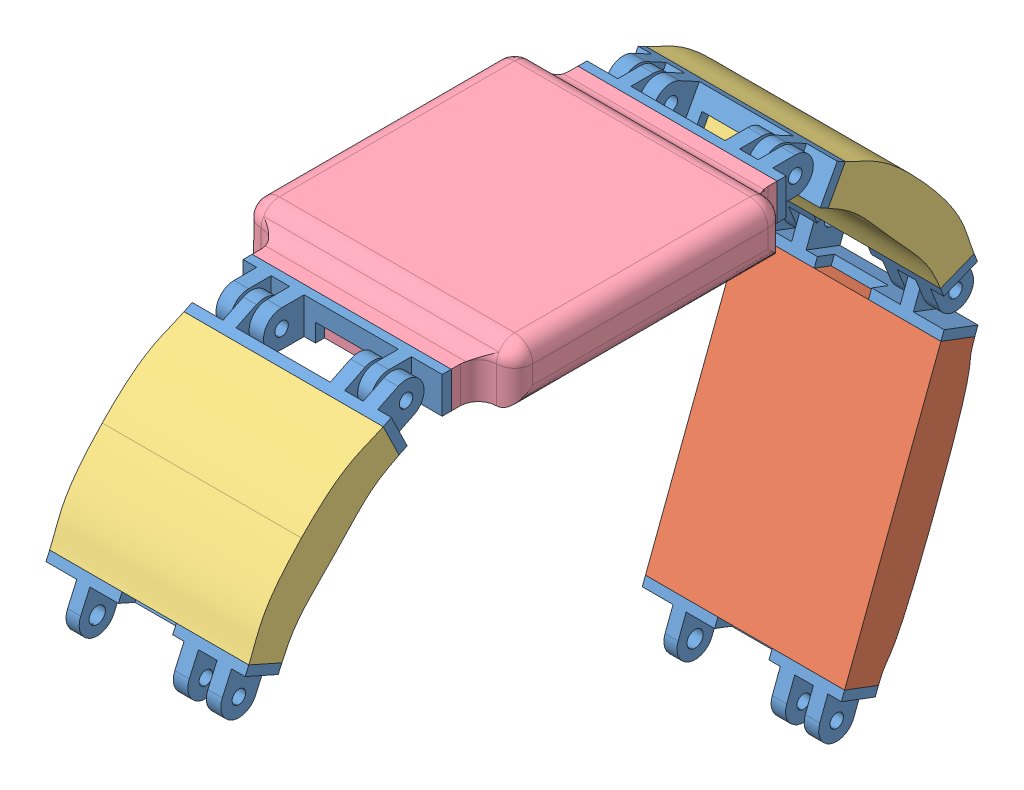
SolidWorks assembly Assem1, configuration Default. Lengths in mm.
Overall size (30 60.99 84.41).
12 component instances, 4 part files, 27 mates.
Components (placement in the parent):
- moddem-1: moddem [Default] at (41.8635 -9.7694 -15.7853) x (1 0 0) z (0 0.934966 -0.354736) size (22 4 5.5)
- moddem-2: moddem [Default] at (41.8635 -44.3632 -2.66) x (-1 0 0) z (0 -0.934966 0.354736) size (22 4 5.5)
- moddem-3: moddem [Default] at (41.8635 10.048 44.925) size (22 4 5.5)
- moddem-4: moddem [Default] at (41.8635 10.048 1.925) x (-1 0 0) z (0 0 -1) size (22 4 5.5)
- moddem-5: moddem [Default] at (41.8635 10.048 44.925) x (-1 0 0) z (0 0.438284 -0.898836) size (22 4 5.5)
- moddem-6: moddem [Default] at (41.8635 -9.0688 63.3894) x (-1 0 0) z (0 -0.913506 0.406825) size (22 4 5.5)
- moddem-7: moddem [Default] at (41.8635 -9.7694 -15.7853) x (-1 0 0) z (0 -0.928574 -0.371147) size (22 4 5.5)
- moddem-8: moddem [Default] at (41.8635 10.048 1.925) x (1 0 0) z (0 0.472761 0.881191) size (22 4 5.5)
- module1-1: module1 [Default] at (30.8635 -26.4386 -7.5684) x (1 0 0) z (0 0.934966 -0.354736) size (22 5 30)
- module4-2: module4 [Default] at (30.8635 0.3363 -7.1506) x (1 0 0) z (0 0.745635 0.666355) size (22 6 21.37)
- module4-1: module4 [Default] at (30.8635 0.695 54.3698) x (1 0 0) z (0 -0.719273 0.694728) size (22 6 21.37)
- module3-1: module3 [Default] at (41.8635 8.048 23.425) x (0 0 1) z (-1 0 0) size (36 6 30)
Mates (geometry in assembly coordinates):
- Coincident1: coincident anti-aligned: plane of module1-1 through (52.8635 -12.3323 -12.6738) normal (0 0.934966 -0.354736); plane of moddem-1 through (30.8635 -13.0418 -14.5437) normal (0 -0.934966 0.354736)
- Coincident2: coincident aligned: line of module1-1 through (52.8635 -13.7513 -16.4136) axis (0 0.354736 0.934966); line of moddem-1 through (52.8635 -13.7513 -16.4136) axis (0 0.354736 0.934966)
- Coincident3: coincident anti-aligned: line of module1-1 through (52.8635 -13.7513 -16.4136) axis (-1 0 0); line of moddem-1 through (30.8635 -13.7513 -16.4136) axis (1 0 0)
- Coincident4: coincident anti-aligned: plane of module1-1 through (52.8635 -40.3813 -2.0317) normal (0 -0.934966 0.354736); plane of moddem-2 through (52.8635 -41.0908 -3.9016) normal (0 0.934966 -0.354736)
- Coincident5: coincident anti-aligned: line of module1-1 through (52.8635 -40.3813 -2.0317) axis (0 -0.354736 -0.934966); line of moddem-2 through (52.8635 -41.8002 -5.7715) axis (0 0.354736 0.934966)
- Coincident6: coincident aligned: line of module1-1 through (52.8635 -41.8002 -5.7715) axis (-1 0 0); line of moddem-2 through (52.8635 -41.8002 -5.7715) axis (-1 0 0)
- Coincident7: coincident anti-aligned: plane of module3-1 through (41.8635 12.048 41.425) normal (0 0 1); plane of moddem-3 through (30.8635 10.048 41.425) normal (0 0 -1)
- Coincident8: coincident anti-aligned: line of module3-1 through (52.8635 12.048 41.425) axis (-1 0 0); line of moddem-3 through (30.8635 12.048 41.425) axis (1 0 0)
- Coincident9: coincident aligned: line of module3-1 through (52.8635 12.048 41.425) axis (0 -1 0); line of moddem-3 through (52.8635 12.048 41.425) axis (0 -1 0)
- Coincident10: coincident anti-aligned: plane of module3-1 through (41.8635 12.048 5.425) normal (0 0 -1); plane of moddem-4 through (52.8635 10.048 5.425) normal (0 0 1)
- Coincident11: coincident aligned: line of module3-1 through (52.8635 12.048 5.425) axis (-1 0 0); line of moddem-4 through (52.8635 12.048 5.425) axis (-1 0 0)
- Coincident12: coincident aligned: line of module3-1 through (52.8635 12.048 5.425) axis (0 -1 0); line of moddem-4 through (52.8635 12.048 5.425) axis (0 -1 0)
- Coincident13: coincident anti-aligned: plane of module4-1 through (52.8635 -6.6851 60.1385) normal (0 -0.913506 0.406825); plane of moddem-6 through (52.8635 -5.8715 61.9655) normal (0 0.913506 -0.406825)
- Coincident14: coincident aligned: line of module4-1 through (52.8635 -6.6851 60.1385) axis (-1 0 0); line of moddem-6 through (52.8635 -6.6851 60.1385) axis (-1 0 0)
- Coincident15: coincident anti-aligned: line of module4-1 through (52.8635 -5.0578 63.7925) axis (0 -0.406825 -0.913506); line of moddem-6 through (52.8635 -6.6851 60.1385) axis (0 0.406825 0.913506)
- Coincident16: coincident anti-aligned: plane of module4-1 through (52.8635 6.7163 47.1944) normal (0 0.438284 -0.898836); plane of moddem-5 through (52.8635 8.514 48.0709) normal (0 -0.438284 0.898836)
- Coincident17: coincident aligned: line of module4-1 through (52.8635 10.3116 48.9475) axis (-1 0 0); line of moddem-5 through (52.8635 10.3116 48.9475) axis (-1 0 0)
- Coincident18: coincident anti-aligned: line of module4-1 through (52.8635 6.7163 47.1944) axis (0 0.898836 0.438284); line of moddem-5 through (52.8635 10.3116 48.9475) axis (0 -0.898836 -0.438284)
- Coincident21: coincident anti-aligned: circle of moddem-3; circle of moddem-5
- Coincident23: coincident anti-aligned: plane of module4-2 through (52.8635 -7.2617 -12.6291) normal (0 -0.928574 -0.371147); plane of moddem-7 through (52.8635 -6.5194 -14.4863) normal (0 0.928574 0.371147)
- Coincident24: coincident aligned: line of module4-2 through (52.8635 -5.7771 -16.3434) axis (-1 0 0); line of moddem-7 through (52.8635 -5.7771 -16.3434) axis (-1 0 0)
- Coincident25: coincident anti-aligned: line of module4-2 through (30.8635 -7.2617 -12.6291) axis (0 0.371147 -0.928574); line of moddem-7 through (30.8635 -5.7771 -16.3434) axis (0 -0.371147 0.928574)
- Coincident26: coincident anti-aligned: plane of module4-2 through (52.8635 6.6309 -0.2136) normal (0 0.472761 0.881191); plane of moddem-8 through (30.8635 8.3933 -1.1592) normal (0 -0.472761 -0.881191)
- Coincident27: coincident aligned: line of module4-2 through (30.8635 10.1557 -2.1047) axis (0 -0.881191 0.472761); line of moddem-8 through (30.8635 10.1557 -2.1047) axis (0 -0.881191 0.472761)
- Coincident29: coincident anti-aligned: line of module4-2 through (52.8635 10.1557 -2.1047) axis (-1 0 0); line of moddem-8 through (30.8635 10.1557 -2.1047) axis (1 0 0)
- Coincident30: coincident anti-aligned: circle of moddem-4; circle of moddem-8
- Coincident31: coincident anti-aligned: circle of moddem-1; circle of moddem-7
